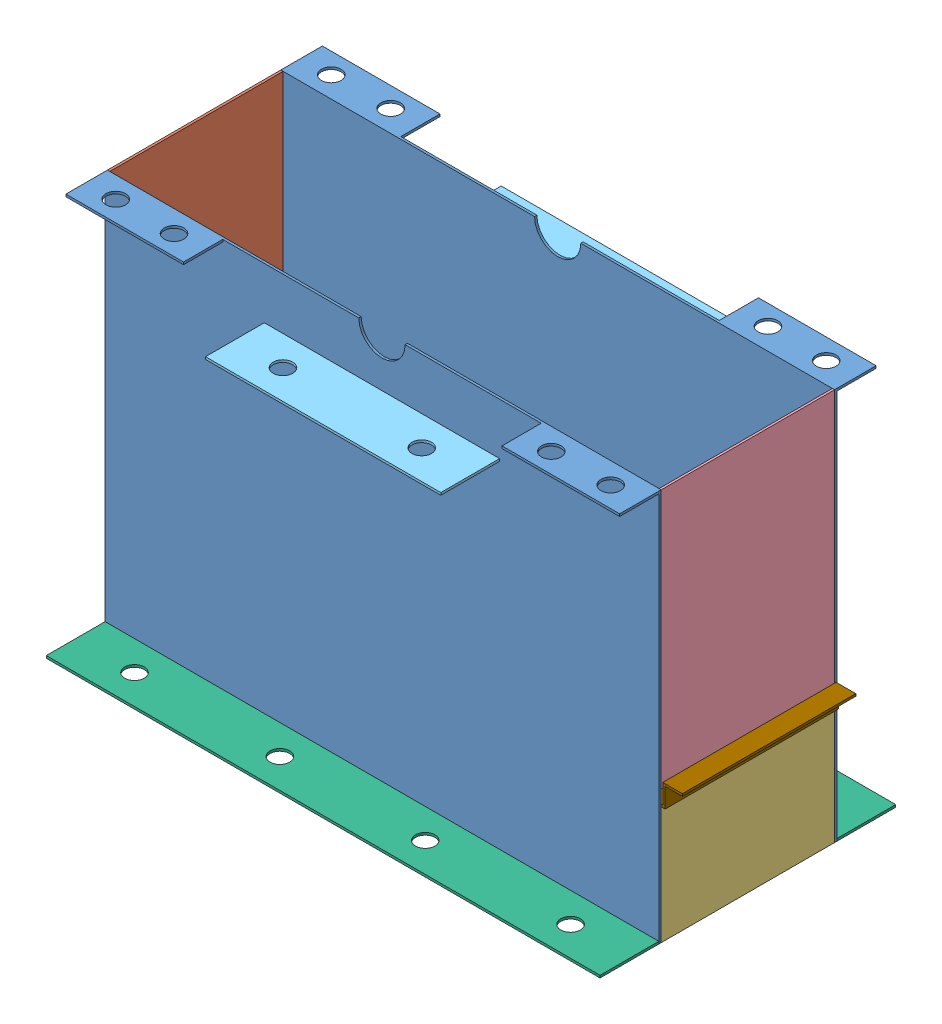
SolidWorks assembly Bottom Assembly, configuration Default. Lengths in mm.
Overall size (372.36 254 191.51).
13 component instances, 9 part files, 34 mates.
Components (placement in the parent):
- Bottom Assembly - Center Casing-1: Bottom Assembly - Center Casing [Default] at (69.4283 125.4695 280.1824) size (358.64 254 26.92)
- Bottom Assembly - Center Casing-2: Bottom Assembly - Center Casing [Default] at (69.4283 125.4695 167.9144) x (-1 0 0) z (0 0 -1) size (358.64 254 26.92)
- Bottom Assembly - Outer Casing-1: Bottom Assembly - Outer Casing [Default] at (-108.3717 49.2695 167.9144) x (0 0 1) z (-1 0 0) size (112.27 254 1.52)
- Bottom Assembly - Outer Casing with slot bottom-1: Bottom Assembly - Outer Casing with slot bottom [Default] at (247.2283 49.2695 280.1824) x (0 0 -1) z (1 0 0) size (112.27 76.2 1.52)
- Bottom Assembly - Outer Casing with slot top-1: Bottom Assembly - Outer Casing with slot top [Default] at (69.5527 303.2695 167.9144) size (1.39 167.8 112.27)
- Bottom Assembly - Bearing Support-1: Bottom Assembly - Bearing Support [Default] at (145.6283 268.4505 128.2954) x (-1 0 0) z (0 0 -1) size (152.4 1.52 38.1)
- Bottom Assembly - Bearing Support-2: Bottom Assembly - Bearing Support [Default] at (-6.7717 268.4505 319.8013) size (152.4 1.52 38.1)
- Bottom Assembly - Supports-1: Bottom Assembly - Supports [Default] at (-109.8907 49.2695 319.8013) size (358.64 1.52 38.1)
- Bottom Assembly - Supports-2: Bottom Assembly - Supports [Default] at (248.7472 49.2695 128.2954) x (-1 0 0) z (0 0 -1) size (358.64 1.52 38.1)
- Bottom Assembly - Mesh Ledge Short-2: Bottom Assembly - Mesh Ledge Short [Default] at (-108.3717 125.4695 280.1824) x (1 0 0) z (0 1 0) size (6.35 112.27 1.52)
- Bottom Assembly - Mesh Ledge Long-3: Bottom Assembly - Mesh Ledge Long [Default] at (-102.0217 123.9505 280.1824) x (0 0 -1) z (1 0 0) size (6.35 1.52 349.25)
- Bottom Assembly - Mesh Ledge Long-4: Bottom Assembly - Mesh Ledge Long [Default] at (247.2283 123.9505 167.9144) x (0 0 1) z (-1 0 0) size (6.35 1.52 349.25)
- Bottom Assembly - Mesh-2: Bottom Assembly - Mesh [Default] at (-108.3717 125.4695 280.1824) size (370.84 14.22 112.27)
Mates (geometry in assembly coordinates):
- Coincident1: coincident aligned: line of Bottom Assembly - Center Casing-1 through (248.7472 49.2695 280.1824) axis (0 1 0); line of Bottom Assembly - Outer Casing with slot top-1 through (248.7472 135.4695 280.1824) axis (0 1 0)
- Coincident2: coincident aligned: plane of Bottom Assembly - Center Casing-1 through (84.4283 303.2695 281.7013) normal (0 1 0); plane of Bottom Assembly - Outer Casing with slot top-1 through (247.3527 303.2695 280.1824) normal (0 1 0)
- Coincident3: coincident aligned: plane of Bottom Assembly - Center Casing-1 through (248.7472 303.2695 281.7013) normal (1 0 0); plane of Bottom Assembly - Outer Casing with slot top-1 through (248.7472 303.2695 280.1824) normal (1 0 0)
- Coincident4: coincident anti-aligned: line of Bottom Assembly - Center Casing-1 through (248.7472 49.2695 280.1824) axis (0 1 0); line of Bottom Assembly - Outer Casing with slot bottom-1 through (248.7472 125.4695 280.1824) axis (0 -1 0)
- Coincident5: coincident aligned: plane of Bottom Assembly - Center Casing-1 through (248.7472 303.2695 281.7013) normal (1 0 0); plane of Bottom Assembly - Outer Casing with slot bottom-1 through (248.7472 49.2695 280.1824) normal (1 0 0)
- Coincident6: coincident aligned: plane of Bottom Assembly - Center Casing-1 through (-109.8907 49.2695 281.7013) normal (0 -1 0); plane of Bottom Assembly - Outer Casing with slot bottom-1 through (248.7472 49.2695 280.1824) normal (0 -1 0)
- Coincident7: coincident anti-aligned: line of Bottom Assembly - Center Casing-1 through (-109.8907 303.2695 280.1824) axis (0 -1 0); line of Bottom Assembly - Outer Casing-1 through (-109.8907 49.2695 280.1824) axis (0 1 0)
- Coincident8: coincident aligned: plane of Bottom Assembly - Center Casing-1 through (-109.8907 303.2695 281.7013) normal (-1 0 0); plane of Bottom Assembly - Outer Casing-1 through (-109.8907 49.2695 167.9144) normal (-1 0 0)
- Coincident9: coincident aligned: plane of Bottom Assembly - Center Casing-1 through (-109.8907 303.2695 281.7013) normal (0 1 0); plane of Bottom Assembly - Outer Casing-1 through (-109.8907 303.2695 167.9144) normal (0 1 0)
- Coincident11: coincident anti-aligned: line of Bottom Assembly - Center Casing-2 through (248.7472 303.2695 167.9144) axis (0 -1 0); line of Bottom Assembly - Outer Casing with slot top-1 through (248.7472 135.4695 167.9144) axis (0 1 0)
- Coincident12: coincident anti-aligned: line of Bottom Assembly - Center Casing-2 through (-109.8907 49.2695 167.9144) axis (0 1 0); line of Bottom Assembly - Outer Casing-1 through (-109.8907 303.2695 167.9144) axis (0 -1 0)
- Coincident13: coincident aligned: plane of Bottom Assembly - Center Casing-2 through (248.7472 303.2695 166.3954) normal (0 1 0); plane of Bottom Assembly - Outer Casing with slot top-1 through (247.3527 303.2695 280.1824) normal (0 1 0)
- Coincident29: coincident anti-aligned: plane of Bottom Assembly - Center Casing-1 through (69.4283 303.2695 281.7013) normal (0 0 1); plane of Bottom Assembly - Bearing Support-2 through (145.6283 268.4505 281.7013) normal (0 0 -1)
- Coincident30: coincident anti-aligned: plane of Bottom Assembly - Center Casing-2 through (69.4283 303.2695 166.3954) normal (0 0 -1); plane of Bottom Assembly - Bearing Support-1 through (-6.7717 268.4505 166.3954) normal (0 0 1)
- Coincident31: coincident: point of assembly; point of Bottom Assembly - Center Casing-1; moEndPointRef_w of Bottom Assembly - Bearing Support-2
- Parallel2: parallel anti-aligned: line of Bottom Assembly - Center Casing-1 through (-27.7312 303.2695 281.7013) axis (1 0 0); line of Bottom Assembly - Bearing Support-2 through (145.6283 269.9695 281.7013) axis (-1 0 0)
- Coincident33: coincident: point of assembly; point of Bottom Assembly - Center Casing-2; moEndPointRef_w of Bottom Assembly - Bearing Support-1
- Parallel3: parallel anti-aligned: line of Bottom Assembly - Center Casing-2 through (166.5877 303.2695 166.3954) axis (-1 0 0); line of Bottom Assembly - Bearing Support-1 through (-6.7717 269.9695 166.3954) axis (1 0 0)
- Coincident35: coincident anti-aligned: plane of Bottom Assembly - Center Casing-2 through (69.4283 303.2695 166.3954) normal (0 0 -1); plane of Bottom Assembly - Supports-2 through (-109.8907 49.2695 166.3954) normal (0 0 1)
- Coincident36: coincident anti-aligned: plane of Bottom Assembly - Center Casing-1 through (69.4283 303.2695 281.7013) normal (0 0 1); plane of Bottom Assembly - Supports-1 through (248.7472 49.2695 281.7013) normal (0 0 -1)
- Coincident37: coincident anti-aligned: line of Bottom Assembly - Center Casing-1 through (-109.8907 49.2695 281.7013) axis (1 0 0); line of Bottom Assembly - Supports-1 through (248.7472 49.2695 281.7013) axis (-1 0 0)
- Coincident38: coincident anti-aligned: line of Bottom Assembly - Center Casing-1 through (-109.8907 301.7505 281.7013) axis (0 -1 0); line of Bottom Assembly - Supports-1 through (-109.8907 49.2695 281.7013) axis (0 1 0)
- Coincident39: coincident anti-aligned: line of Bottom Assembly - Center Casing-2 through (248.7472 49.2695 166.3954) axis (-1 0 0); line of Bottom Assembly - Supports-2 through (-109.8907 49.2695 166.3954) axis (1 0 0)
- Coincident40: coincident aligned: line of Bottom Assembly - Center Casing-2 through (-109.8907 49.2695 166.3954) axis (0 1 0); line of Bottom Assembly - Supports-2 through (-109.8907 49.2695 166.3954) axis (0 1 0)
- Coincident52: coincident aligned: line of Bottom Assembly - Center Casing-1 through (-109.8907 125.4695 280.1824) axis (1 0 0); line of Bottom Assembly - Mesh Ledge Short-2 through (-108.3717 125.4695 280.1824) axis (1 0 0)
- Coincident54: coincident anti-aligned: line of Bottom Assembly - Center Casing-2 through (248.7472 125.4695 167.9144) axis (-1 0 0); line of Bottom Assembly - Mesh Ledge Short-2 through (-108.3717 125.4695 167.9144) axis (1 0 0)
- Coincident55: coincident anti-aligned: plane of Bottom Assembly - Outer Casing-1 through (-108.3717 49.2695 167.9144) normal (1 0 0); plane of Bottom Assembly - Mesh Ledge Short-2 through (-108.3717 125.4695 167.9144) normal (-1 0 0)
- Coincident56: coincident anti-aligned: line of Bottom Assembly - Mesh Ledge Short-2 through (-102.0217 125.4695 167.9144) axis (0 0 1); line of Bottom Assembly - Mesh Ledge Long-4 through (-102.0217 125.4695 174.2644) axis (0 0 -1)
- Coincident57: coincident anti-aligned: line of Bottom Assembly - Center Casing-2 through (248.7472 125.4695 167.9144) axis (-1 0 0); line of Bottom Assembly - Mesh Ledge Long-4 through (-102.0217 125.4695 167.9144) axis (1 0 0)
- Coincident58: coincident anti-aligned: line of Bottom Assembly - Center Casing-1 through (-109.8907 125.4695 280.1824) axis (1 0 0); line of Bottom Assembly - Mesh Ledge Long-3 through (247.2283 125.4695 280.1824) axis (-1 0 0)
- Coincident59: coincident aligned: line of Bottom Assembly - Mesh Ledge Short-2 through (-102.0217 125.4695 167.9144) axis (0 0 1); line of Bottom Assembly - Mesh Ledge Long-3 through (-102.0217 125.4695 273.8324) axis (0 0 1)
- Coincident60: coincident anti-aligned: plane of Bottom Assembly - Outer Casing-1 through (-108.3717 49.2695 167.9144) normal (1 0 0); plane of Bottom Assembly - Mesh-2 through (-108.3717 126.9884 280.1824) normal (-1 0 0)
- Coincident61: coincident anti-aligned: plane of Bottom Assembly - Mesh Ledge Short-2 through (-108.3717 125.4695 167.9144) normal (0 1 0); plane of Bottom Assembly - Mesh-2 through (-108.3717 125.4695 280.1824) normal (0 -1 0)
- Coincident62: coincident anti-aligned: plane of Bottom Assembly - Center Casing-1 through (69.4283 303.2695 280.1824) normal (0 0 -1); plane of Bottom Assembly - Mesh-2 through (-108.3717 126.9884 280.1824) normal (0 0 1)
